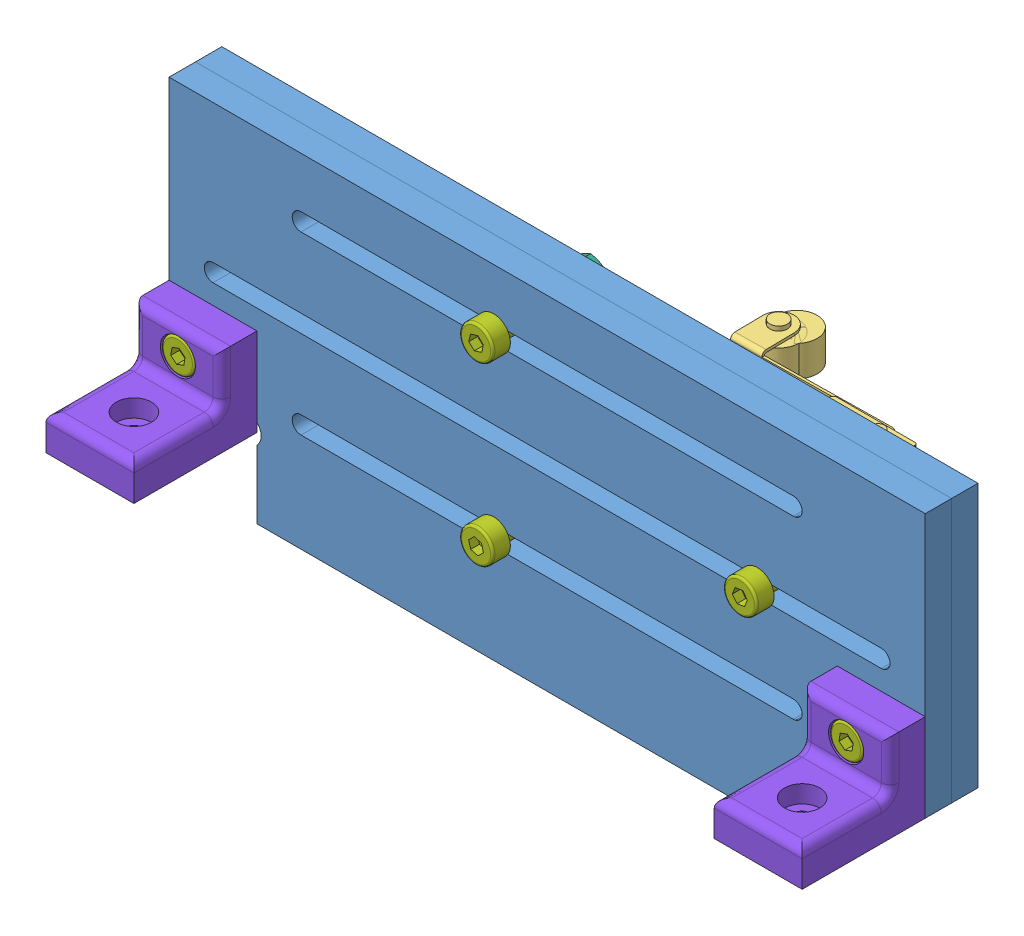
SolidWorks assembly cfc_ferme, configuration Défaut. Lengths in mm.
Overall size (86 39 42.4).
21 component instances, 8 part files, 46 mates.
Components (placement in the parent):
- cfc-platine-1: cfc-platine [Défaut] at (140.8628 -70 0) x (0 0 1) z (0 -1 0) size (3 86 39)
- Grove microswitch v1.0-1: Grove microswitch v1.0 [Défaut] at (-37.098 22.25 -3.344) x (1 0 0) z (0 1 0) size (41.8 22.4 23.6)
  - PCB grove 20x40-1: PCB grove 20x40 [Défaut] at (-1.988 -1.344 0) size (41.8 1.6 23.6)
  - microswitch 10T85-1: microswitch 10T85 [Défaut] at (9.562 0.256 0) size (22.48 22.4 6.4)
  - Connecteur Grove (coudé CMS)-1: Connecteur Grove (coudé CMS) [Défaut] at (-21.488 0.256 0) x (0 0 -1) z (0 1 0) size (12 10 5)
- entretoise-grove-1: entretoise-grove [Défaut] at (-19.086 22.25 -2) x (1 0.000242 0) z (0 0 1) size (4 4 2)
- entretoise-grove-2: entretoise-grove [Défaut] at (-49.086 12.25 -2) size (4 4 2)
- entretoise-grove-3: entretoise-grove [Défaut] at (-49.086 32.25 -2) size (4 4 2)
- ecrou-h-1: ecrou-h [6007 HU M2] at (-19.086 22.25 -3.6) x (0.5 0.866025 0) z (0.866025 -0.5 0) size (4 1.6 4.62)
- ecrou-h-2: ecrou-h [6007 HU M2] at (-49.086 12.25 -3.6) x (1 0 0) z (0 -1 0) size (4 1.6 4.62)
- ecrou-h-3: ecrou-h [6007 HU M2] at (-49.086 32.25 -3.6) x (-0.5 0.866025 0) z (0.866025 0.5 0) size (4 1.6 4.62)
- vis-chc-1: vis-chc [Vis CHC M2x12] at (-49.086 12.25 6) x (0.689734 0.724063 0) z (0.724063 -0.689734 0) size (3.8 14 3.8)
- vis-chc-2: vis-chc [Vis CHC M2x12] at (-49.086 32.25 6) x (-0.193562 -0.981088 0) z (-0.981088 0.193562 0) size (3.8 14 3.8)
- vis-chc-3: vis-chc [Vis CHC M2x12] at (-19.086 22.25 6) x (-0.643508 0.765439 0) z (0.765439 0.643508 0) size (3.8 14 3.8)
- ecrou-h-5: ecrou-h [6007 HU M2] at (-81 16 -1.6) x (1 0 0) z (0 1 0) size (4 1.6 4.62)
- ecrou-h-6: ecrou-h [6007 HU M2] at (-5 16 -1.6) x (1 0 0) z (0 1 0) size (4 1.6 4.62)
- vis-chc-6: vis-chc [Vis CHC M2x10] at (-5 16 8) x (-0.923728 -0.383049 0) z (-0.383049 0.923728 0) size (3.8 12 3.8)
- vis-chc-7: vis-chc [Vis CHC M2x10] at (-81 16 8) x (-0.923728 -0.383049 0) z (-0.383049 0.923728 0) size (3.8 12 3.8)
- cfc-platine-2: cfc-platine [Défaut] at (140.8628 -70 3) x (0 0 1) z (0 -1 0) size (3 86 39)
- equerre-basse-1: equerre-basse [Défaut] at (-81 9 6) size (10 10 14)
- equerre-basse-2: equerre-basse [Défaut] at (-5 9 6) size (10 10 14)
Mates (geometry in assembly coordinates):
- Coïncidente1: coincident anti-aligned: plane of cfc-platine-1 through (-8.8686 8.8686 0) normal (0 0 -1)
- Coïncidente2: coincident anti-aligned: plane of cfc-platine-1 through (-10 0 3) normal (0 -1 0)
- Coaxiale1: concentric anti-aligned: cylinder of Grove microswitch v1.0-1/PCB grove 20x40-1 through (-49.086 32.25 -3.6) axis (0 0 1) radius 1.1; cylinder of entretoise-grove-3 through (-49.086 32.25 0) axis (0 0 -1) radius 1
- Coïncidente4: coincident anti-aligned: plane of Grove microswitch v1.0-1/PCB grove 20x40-1 through (-39.086 22.25 -2) normal (0 0 1); plane of entretoise-grove-3 through (-49.086 32.25 -2) normal (0 0 -1)
- Coaxiale2: concentric anti-aligned: cylinder of Grove microswitch v1.0-1/PCB grove 20x40-1 through (-19.086 22.25 -3.6) axis (0 0 1) radius 1.1; cylinder of entretoise-grove-1 through (-19.086 22.25 0) axis (0 0 -1) radius 1
- Coïncidente5: coincident anti-aligned: plane of Grove microswitch v1.0-1/PCB grove 20x40-1 through (-39.086 22.25 -2) normal (0 0 1); plane of entretoise-grove-1 through (-19.086 22.25 -2) normal (0 0 -1)
- Coaxiale3: concentric anti-aligned: cylinder of Grove microswitch v1.0-1/PCB grove 20x40-1 through (-49.086 12.25 -3.6) axis (0 0 1) radius 1.1; cylinder of entretoise-grove-2 through (-49.086 12.25 0) axis (0 0 -1) radius 1
- Coïncidente6: coincident anti-aligned: plane of Grove microswitch v1.0-1/PCB grove 20x40-1 through (-39.086 22.25 -2) normal (0 0 1); plane of entretoise-grove-2 through (-49.086 12.25 -2) normal (0 0 -1)
- Coïncidente7: coincident anti-aligned: plane of cfc-platine-1 through (-8.8686 8.8686 0) normal (0 0 -1); plane of entretoise-grove-1 through (-19.086 22.25 0) normal (0 0 1)
- Parallèle4: parallel anti-aligned: plane of cfc-platine-1 through (-86 39 3) normal (-1 0 0); plane of Grove microswitch v1.0-1/PCB grove 20x40-1 through (-19.086 22.25 -3.6) normal (1 0 0)
- Parallèle3: parallel anti-aligned: plane of cfc-platine-1 through (-10 0 3) normal (0 -1 0); plane of Grove microswitch v1.0-1/PCB grove 20x40-1 through (-39.086 32.25 -3.6) normal (0 1 0)
- Coaxiale7: concentric aligned: cylinder of ecrou-h-2 through (-49.086 12.25 -5.2) axis (0 0 1) radius 0.7835; cylinder of vis-chc-1 through (-49.086 12.25 -6) axis (0 0 1) radius 1
- Coaxiale8: concentric aligned: cylinder of ecrou-h-3 through (-49.086 32.25 -5.2) axis (0 0 1) radius 0.7835; cylinder of vis-chc-2 through (-49.086 32.25 -6) axis (0 0 1) radius 1
- Coaxiale9: concentric aligned: cylinder of ecrou-h-1 through (-19.086 22.25 -5.2) axis (0 0 1) radius 0.7835; cylinder of vis-chc-3 through (-19.086 22.25 -6) axis (0 0 1) radius 1
- Tangent1: tangent anti-aligned: plane of cfc-platine-1 through (-5 21.25 3) normal (0 1 0); cylinder of vis-chc-3 through (-19.086 22.25 -6) axis (0 0 1) radius 1
- Coïncidente8: coincident anti-aligned: plane of Grove microswitch v1.0-1/PCB grove 20x40-1 through (-39.086 22.25 -3.6) normal (0 0 -1); plane of ecrou-h-1 through (-19.086 24.5594 -3.6) normal (0 0 1)
- Parallèle10: parallel anti-aligned: plane of Grove microswitch v1.0-1/microswitch 10T85-1 through (-21.086 25.25 -13.9) normal (1 0 0); plane of ecrou-h-1 through (-21.086 23.4047 -5.2) normal (-1 0 0)
- Coïncidente11: coincident anti-aligned: plane of Grove microswitch v1.0-1/PCB grove 20x40-1 through (-39.086 22.25 -3.6) normal (0 0 -1); plane of ecrou-h-2 through (-47.086 13.4047 -3.6) normal (0 0 1)
- Parallèle11: parallel anti-aligned: plane of cfc-platine-1 through (-86 39 3) normal (-1 0 0); plane of ecrou-h-2 through (-47.086 11.0953 -5.2) normal (1 0 0)
- Coïncidente13: coincident anti-aligned: plane of Grove microswitch v1.0-1/PCB grove 20x40-1 through (-39.086 22.25 -3.6) normal (0 0 -1); plane of ecrou-h-3 through (-51.086 33.4047 -3.6) normal (0 0 1)
- Parallèle12: parallel aligned: plane of cfc-platine-1 through (-86 39 3) normal (-1 0 0); plane of ecrou-h-3 through (-51.086 33.4047 -5.2) normal (-1 0 0)
- Coïncidente15: coincident anti-aligned: plane of cfc-platine-1 through (-8.8686 8.8686 3) normal (0 0 1); plane of cfc-platine-2 through (-8.8686 8.8686 3) normal (0 0 -1)
- Coïncidente16: coincident aligned: plane of cfc-platine-1 through (-10 0 3) normal (0 -1 0); plane of cfc-platine-2 through (-10 0 6) normal (0 -1 0)
- Coïncidente17: coincident aligned: plane of cfc-platine-1 through (-86 39 3) normal (-1 0 0); plane of cfc-platine-2 through (-86 39 6) normal (-1 0 0)
- Coïncidente19: coincident anti-aligned: plane of vis-chc-2 through (-49.086 32.25 6) normal (0 0 -1); plane of cfc-platine-2 through (-8.8686 8.8686 6) normal (0 0 1)
- Coaxiale10: concentric aligned: cylinder of Grove microswitch v1.0-1/PCB grove 20x40-1 through (-49.086 32.25 -3.6) axis (0 0 1) radius 1.1; cylinder of vis-chc-2 through (-49.086 32.25 -6) axis (0 0 1) radius 1
- Coaxiale11: concentric aligned: cylinder of Grove microswitch v1.0-1/PCB grove 20x40-1 through (-19.086 22.25 -3.6) axis (0 0 1) radius 1.1; cylinder of vis-chc-3 through (-19.086 22.25 -6) axis (0 0 1) radius 1
- Coïncidente21: coincident anti-aligned: plane of vis-chc-3 through (-19.086 22.25 6) normal (0 0 -1); plane of cfc-platine-2 through (-8.8686 8.8686 6) normal (0 0 1)
- Coïncidente22: coincident anti-aligned: plane of vis-chc-1 through (-49.086 12.25 6) normal (0 0 -1); plane of cfc-platine-2 through (-8.8686 8.8686 6) normal (0 0 1)
- Coaxiale12: concentric aligned: cylinder of Grove microswitch v1.0-1/PCB grove 20x40-1 through (-49.086 12.25 -3.6) axis (0 0 1) radius 1.1; cylinder of vis-chc-1 through (-49.086 12.25 -6) axis (0 0 1) radius 1
- Coïncidente23: coincident aligned: plane of cfc-platine-2 through (-78.726 9 6) normal (0 -1 0); plane of equerre-1 through (-86 9 10) normal (0 -1 0)
- Coïncidente24: coincident anti-aligned: plane of cfc-platine-2 through (-8.8686 8.8686 6) normal (0 0 1); plane of equerre-1 through (-81 9 6) normal (0 0 -1)
- Coaxiale13: concentric anti-aligned: cylinder of cfc-platine-2 through (-81 16 6) axis (0 0 -1) radius 1; cylinder of equerre-1 through (-81 16 6) axis (0 0 1) radius 1
- Coïncidente25: coincident anti-aligned: plane of cfc-platine-2 through (-8.8686 8.8686 6) normal (0 0 1); plane of equerre-2 through (-5 9 6) normal (0 0 -1)
- Coïncidente26: coincident aligned: plane of cfc-platine-2 through (0 9 6) normal (0 -1 0); plane of equerre-2 through (-10 9 10) normal (0 -1 0)
- Coaxiale14: concentric anti-aligned: cylinder of cfc-platine-2 through (-5 16 6) axis (0 0 -1) radius 1; cylinder of equerre-2 through (-5 16 6) axis (0 0 1) radius 1
- Coaxiale16: concentric aligned: cylinder of vis-chc-7 through (-81 16 -2) axis (0 0 1) radius 1; cylinder of equerre-1 through (-81 16 6) axis (0 0 1) radius 1
- Coaxiale17: concentric aligned: cylinder of vis-chc-6 through (-5 16 -2) axis (0 0 1) radius 1; cylinder of equerre-2 through (-5 16 6) axis (0 0 1) radius 1
- Coïncidente28: coincident anti-aligned: plane of vis-chc-6 through (-5 16 8) normal (0 0 -1); plane of equerre-2 through (-5 16 8) normal (0 0 1)
- Coïncidente29: coincident anti-aligned: plane of vis-chc-7 through (-81 16 8) normal (0 0 -1); plane of equerre-1 through (-81 16 8) normal (0 0 1)
- Coaxiale20: concentric anti-aligned: cylinder of ecrou-h-5 through (-81 16 0) axis (0 0 -1) radius 0.7835; cylinder of vis-chc-7 through (-81 16 -2) axis (0 0 1) radius 1
- Coïncidente33: coincident anti-aligned: plane of cfc-platine-1 through (-8.8686 8.8686 0) normal (0 0 -1); plane of ecrou-h-5 through (-79 14.8453 0) normal (0 0 1)
- Parallèle14: parallel aligned: plane of cfc-platine-1 through (-86 39 3) normal (-1 0 0); plane of ecrou-h-5 through (-83 14.8453 0) normal (-1 0 0)
- Coaxiale22: concentric anti-aligned: cylinder of ecrou-h-6 through (-5 16 0) axis (0 0 -1) radius 0.7835; cylinder of vis-chc-6 through (-5 16 -2) axis (0 0 1) radius 1
- Coïncidente35: coincident anti-aligned: plane of cfc-platine-1 through (-8.8686 8.8686 0) normal (0 0 -1); plane of ecrou-h-6 through (-3 14.8453 0) normal (0 0 1)
- Parallèle15: parallel aligned: plane of cfc-platine-1 through (0 9 3) normal (1 0 0); plane of ecrou-h-6 through (-3 17.1547 0) normal (1 0 0)
